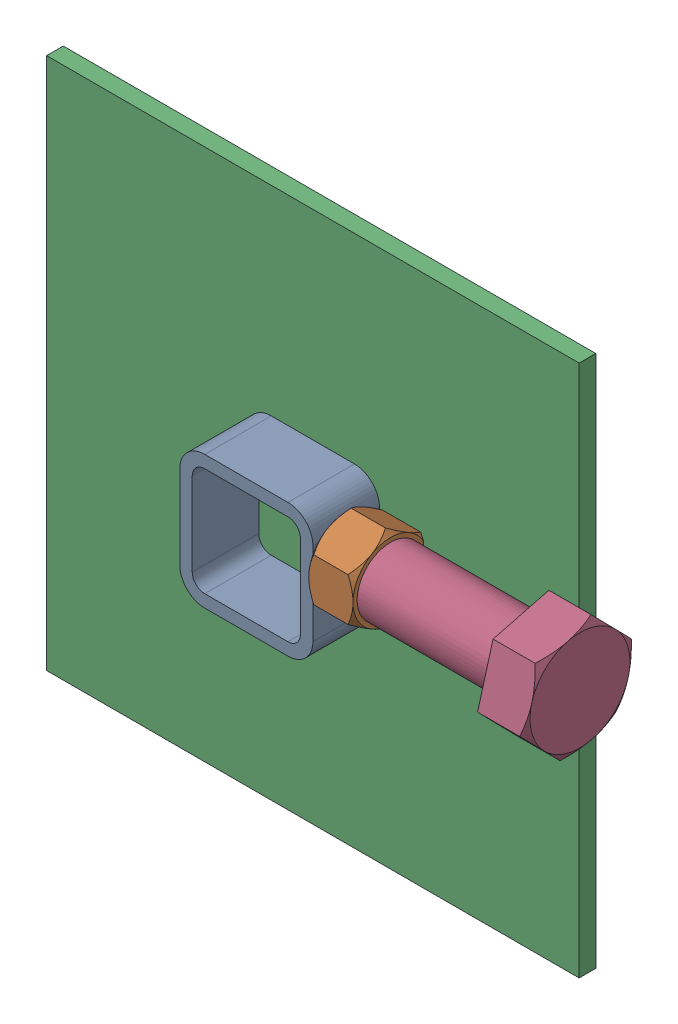
SolidWorks assembly 01-002-00-0(Default), configuration Default. Lengths in mm.
Overall size (216.22 203.2 48.52).
5 component instances, 4 part files, 0 mates.
Components (placement in the parent):
- 01-005-00-0-1: 01-005-00-0 [Default] at origin size (67.69 50.8 28.57)
  - tube square_ai(PreviewCfg)-1: tube square_ai(PreviewCfg) [Default] at origin size (50.8 50.8 25.4)
  - hex nut_ai(HNUT 0.7500-10-D-C)-1: hex nut_ai(HNUT 0.7500-10-D-C) [Default] at (67.691 31.75 0) x (0 0 -1) z (1 0 0) size (28.57 33 16.89)
- 01-006-00-0-1: 01-006-00-0 [Default] at (-76.2 -76.2 -19.05) x (1 0 0) z (0 -1 0) size (203.2 6.35 203.2)
- hex bolt_ai(PreviewCfg)-1: hex bolt_ai(PreviewCfg) [Default] at (140.0175 31.75 0) x (-1 0 0) z (0 -0.268825 -0.963189) size (93.98 43.99 38.1)
